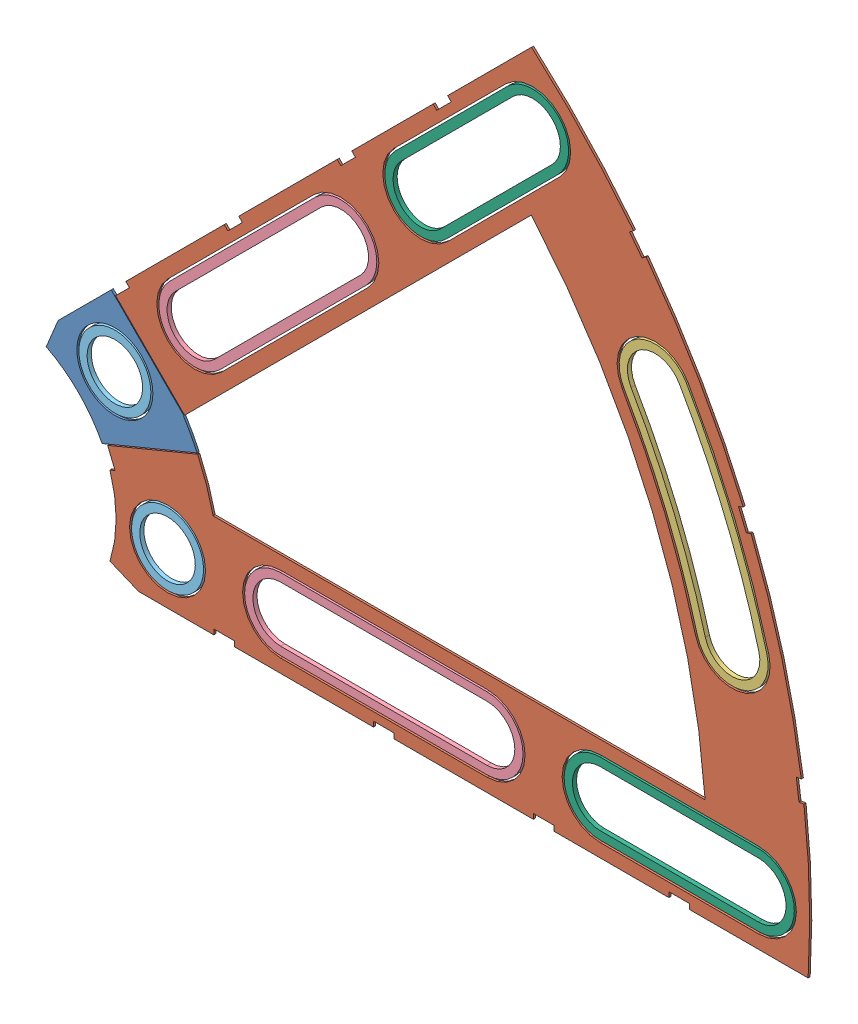
SolidWorks assembly Clover_1_Insul+Pass, configuration Default. Lengths in mm.
Overall size (94.37 82.54 0.51).
9 component instances, 6 part files, 22 mates.
Components (placement in the parent):
- Clover_1_Pass-1: Clover_1_Pass [Default] at (-5.8846 3.1201 26.2738) size (18.66 17.02 0.25)
- Clover_1_Insul-1: Clover_1_Insul [Default] at (-5.8846 3.1201 26.2738) size (86.78 82.54 0.25)
- Clover_Outside_Washer-1: Clover_Outside_Washer [Default] at (-5.8846 3.1201 26.5278) x (0.866025 0.5 0) z (-0.5 0.866025 0) size (12.14 0.51 33.54)
- Clover_Long_Washer-1: Clover_Long_Washer [Default] at (43.0739 3.1201 26.5278) x (1 0 0) z (0 1 0) size (34.42 0.51 8.89)
- Clover_Long_Washer-2: Clover_Long_Washer [Default] at (28.7343 37.7389 26.5278) x (0.707107 0.707107 0) z (-0.707107 0.707107 0) size (34.42 0.51 8.89)
- Round_Washer-1: Round_Washer [Default] at (9.8309 18.8355 26.5278) x (1 0 0) z (0 1 0) size (8.89 0.51 8.89)
- Round_Washer-2: Round_Washer [Default] at (16.3404 3.1201 26.0198) x (1 0 0) z (0 -1 0) size (8.89 0.51 8.89)
- Clover_Med_Washer-1: Clover_Med_Washer [Default] at (54.5525 63.5572 26.5278) x (-0.707107 -0.707107 0) z (0.707107 -0.707107 0) size (28.45 0.51 8.89)
- Clover_Med_Washer-2: Clover_Med_Washer [Default] at (79.5864 3.1201 26.5278) x (1 0 0) z (0 1 0) size (28.45 0.51 8.89)
Mates (geometry in assembly coordinates):
- Coincident1: coincident: plane of Clover_1_Pass-1 through (-5.8846 3.1201 26.5278) normal (0 0 1); plane of Clover_1_Insul-1 through (-5.8846 3.1201 26.5278) normal (0 0 1)
- Concentric1: concentric: circle of Clover_1_Pass-1; circle of Clover_1_Insul-1
- Parallel1: parallel: plane of Clover_1_Pass-1 through (9.3819 27.3667 26.2738) normal (0.707107 0.707107 0); plane of Clover_1_Insul-1 through (21.3076 15.6206 26.2738) normal (-0.707107 -0.707107 0)
- Concentric2: concentric: circle of Clover_Outside_Washer-1; circle of Clover_1_Insul-1
- Concentric3: concentric: circle of Clover_1_Insul-1; circle of Clover_Outside_Washer-1
- Coincident2: coincident: plane of Clover_1_Insul-1 through (-5.8846 3.1201 26.5278) normal (0 0 1); plane of Clover_Outside_Washer-1 through (35.3599 26.9326 26.5278) normal (0 0 1)
- Concentric4: concentric: circle of Clover_1_Insul-1; circle of Clover_Med_Washer-2
- Concentric5: concentric: circle of Clover_1_Insul-1; circle of Clover_Med_Washer-2
- Coincident3: coincident: plane of Clover_1_Insul-1 through (-5.8846 3.1201 26.5278) normal (0 0 1); plane of Clover_Med_Washer-2 through (69.8074 3.1201 26.5278) normal (0 0 1)
- Concentric6: concentric: circle of Clover_1_Insul-1; circle of Clover_Med_Washer-1
- Concentric7: concentric: circle of Clover_1_Insul-1; circle of Clover_Med_Washer-1
- Coincident4: coincident: plane of Clover_1_Insul-1 through (-5.8846 3.1201 26.5278) normal (0 0 1); plane of Clover_Med_Washer-1 through (61.4673 70.472 26.5278) normal (0 0 1)
- Concentric8: concentric: circle of Clover_1_Insul-1; circle of Clover_Long_Washer-1
- Concentric9: concentric: circle of Clover_1_Insul-1; circle of Clover_Long_Washer-1
- Coincident5: coincident: plane of Clover_1_Insul-1 through (-5.8846 3.1201 26.5278) normal (0 0 1); plane of Clover_Long_Washer-1 through (30.3104 3.1201 26.5278) normal (0 0 1)
- Concentric10: concentric: circle of Clover_1_Insul-1; circle of Clover_Long_Washer-2
- Concentric11: concentric: circle of Clover_1_Insul-1; circle of Clover_Long_Washer-2
- Coincident6: coincident: plane of Clover_1_Insul-1 through (-5.8846 3.1201 26.5278) normal (0 0 1); plane of Clover_Long_Washer-2 through (19.7091 28.7138 26.5278) normal (0 0 1)
- Concentric12: concentric: circle of Clover_1_Pass-1; circle of Round_Washer-1
- Coincident7: coincident: plane of Clover_1_Pass-1 through (-5.8846 3.1201 26.5278) normal (0 0 1); plane of Round_Washer-1 through (9.8309 18.8355 26.5278) normal (0 0 1)
- Concentric13: concentric: circle of Clover_1_Insul-1; circle of Round_Washer-2
- Coincident8: coincident: plane of Clover_1_Insul-1 through (-5.8846 3.1201 26.5278) normal (0 0 1); plane of Round_Washer-2 through (16.3404 3.1201 26.5278) normal (0 0 1)
